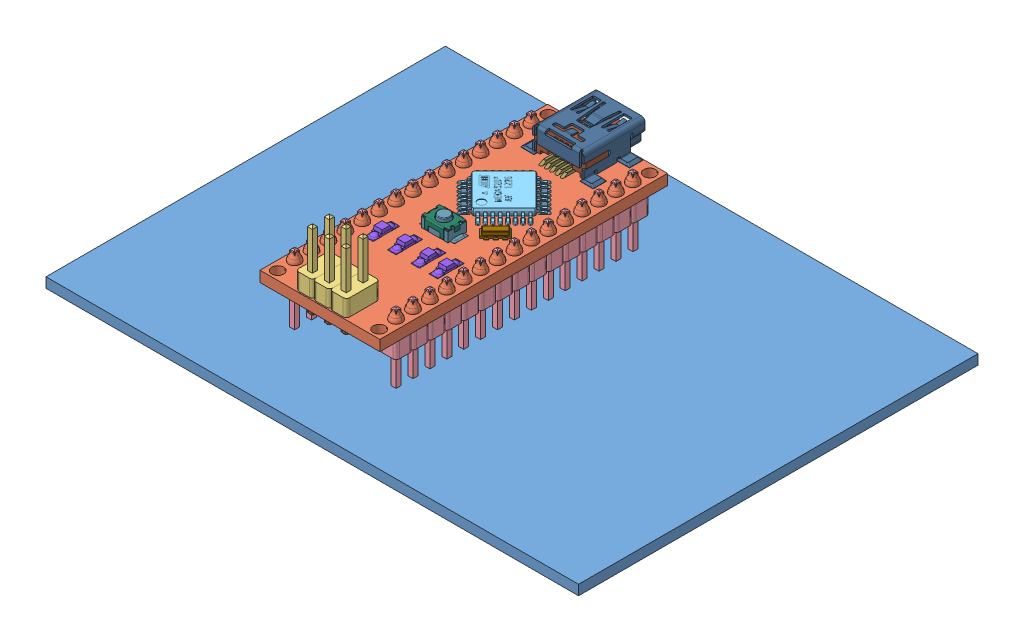
SolidWorks assembly support+nano, configuration Défaut. Lengths in mm.
Overall size (575.83 18.6 259.5).
35 component instances, 19 part files, 3 mates.
Components (placement in the parent):
- support nano-1: support nano [Défaut] at origin size (575.83 1.5 259.5)
- arduino nano-1: arduino nano [Défaut] at (40.4386 8.5 -12.1504) x (0 0 -1) z (1 0 0) size (45 18.6 18)
  - nano-board-1: nano-board [Défaut] at origin size (43.2 4.6 18)
  - 2pin_header__02-1: 2pin_header__02 [Défaut] at (-1.143 1.6 -7.62) size (5 11.75 2.54)
  - 2pin_header__02-2: 2pin_header__02 [Défaut] at (-1.143 1.6 -5.08) size (5 11.75 2.54)
  - 2pin_header__02-3: 2pin_header__02 [Défaut] at (-1.143 1.6 -10.16) size (5 11.75 2.54)
  - 15pin_header__-1: 15pin_header__ [Défaut] x (0 0 1) z (1 0 0) size (2.54 11.75 38.1)
  - 15pin_header__-2: 15pin_header__ [Défaut] at (0 0 -15.24) x (0 0 1) z (1 0 0) size (2.54 11.75 38.1)
  - atmega328-1: atmega328 [Défaut] at (23.85 1.75 -7.62) x (-0.707107 0 0.707107) z (-0.707107 0 -0.707107) size (10 1.11 10)
  - ftdi FT232rl-1: ftdi FT232rl [Défaut] at (29.05 0 -7.67) x (0 0 -1) z (-1 0 0) size (9.25 1.9 10.2)
  - smt_resistor222-1: smt_resistor222 [Défaut] at (21.86 0 -5.8) x (0 0 -1) z (-1 0 0) size (1.7 0.6 3.8)
  - smt_resistor222-2: smt_resistor222 [Défaut] at (21.86 0 -9) x (0 0 -1) z (-1 0 0) size (1.7 0.6 3.8)
  - smt_resistor222-3: smt_resistor222 [Défaut] at (36.75 0 -7.6) x (0 0 -1) z (-1 0 0) size (1.7 0.6 3.8)
  - smt_resistor222-4: smt_resistor222 [Défaut] at (36.75 0 -12) x (0 0 -1) z (-1 0 0) size (1.7 0.6 3.8)
  - smt_resistor222-5: smt_resistor222 [Défaut] at (8.2 0 -2.6) x (0 0 -1) z (-1 0 0) size (1.7 0.6 3.8)
  - led-1: led [Défaut] at (10.4 1.6 -2.8) size (4 0.9 1.55)
  - led-2: led [Défaut] at (10.4 1.6 -5.55) size (4 0.9 1.55)
  - led-3: led [Défaut] at (10.4 1.6 -12.5) size (4 0.9 1.55)
  - led-4: led [Défaut] at (10.4 1.6 -9.05) size (4 0.9 1.55)
  - 16mhz crystal - measured-1: 16mhz crystal - measured [Défaut] at (18.5113 1.6 -3.5541) x (0.707107 0 0.707107) z (-0.707107 0 0.707107) size (3.4 0.8 2)
  - MINIUSBSHELL-1: MINIUSBSHELL [Défaut] at (38.98 1.65 -7.62) x (0 0 1) z (-1 0 0) size (10.9 3.85 9.41)
  - MINIUSBCORE-1: MINIUSBCORE [Défaut] at (32.28 1.65 -7.62) x (0 0 -1) z (1 0 0) size (7.7 4.5 8.2)
  - MINI USB CONTACT-1: MINI USB CONTACT [Défaut] at (33.28 1.65 -9.22) x (0 0 -1) z (1 0 0) size (0.53 2.55 9.41)
  - MINI USB CONTACT-2: MINI USB CONTACT [Défaut] at (33.28 1.65 -8.42) x (0 0 -1) z (1 0 0) size (0.53 2.55 9.41)
  - MINI USB CONTACT-3: MINI USB CONTACT [Défaut] at (33.28 1.65 -7.62) x (0 0 -1) z (1 0 0) size (0.53 2.55 9.41)
  - MINI USB CONTACT-4: MINI USB CONTACT [Défaut] at (33.28 1.65 -6.82) x (0 0 -1) z (1 0 0) size (0.53 2.55 9.41)
  - MINI USB CONTACT-5: MINI USB CONTACT [Défaut] at (33.28 1.65 -6.02) x (0 0 -1) z (1 0 0) size (0.53 2.55 9.41)
  - cap106C-1: cap106C [Défaut] at (37.2 0 -3.3) x (0 0 1) z (1 0 0) size (1.7 1.81 4)
  - cap106C-2: cap106C [Défaut] at (7.9 0 -5.6) x (0 0 -1) z (-1 0 0) size (1.7 1.81 4)
  - reset core-1: reset core [Défaut] at (15.25 1.6 -8.05) x (0 0 -1) z (1 0 0) size (5.2 2.15 2.8)
  - reset shell-1: reset shell [Défaut] at (15.25 3.25 -8.05) size (3 1.65 4)
  - nano - reg-1: nano - reg [Défaut] at (6.1 0 -10.16) x (0 0 -1) z (-1 0 0) size (6.5 1.69 8.3)
  - NANO DIODE-1: NANO DIODE [Défaut] at (11.43 0 -4.2) x (0 0 1) z (1 0 0) size (4.92 1.38 1.7)
  - 189 RESISTOR PACK-1: 189 RESISTOR PACK [Défaut] at (15.75 0 -10.85) x (0 0 1) z (1 0 0) size (3.2 0.51 3)
  - 102 RESISTOR PACK-1: 102 RESISTOR PACK [Défaut] at (15.75 0 -5.2) x (0 0 1) z (1 0 0) size (3.2 0.51 3)
Mates (geometry in assembly coordinates):
- Parallèle2: parallel aligned: plane of support nano-1 through (0 1.5 -60) normal (-1 0 0); plane of arduino nano-1/nano-board-1 through (23.8186 8.5 -8.3304) normal (-1 0 0)
- Parallèle3: parallel aligned: plane of support nano-1 through (80 1.5 0) normal (0 0 1); plane of arduino nano-1/nano-board-1 through (41.8186 8.5 -8.3304) normal (0 0 1)
- Coïncidente4: coincident aligned: plane of support nano-1 through (0 0 0) normal (0 -1 0); plane of arduino nano-1/15pin_header__-1 through (40.3136 0 -47.8354) normal (0 -1 0)
